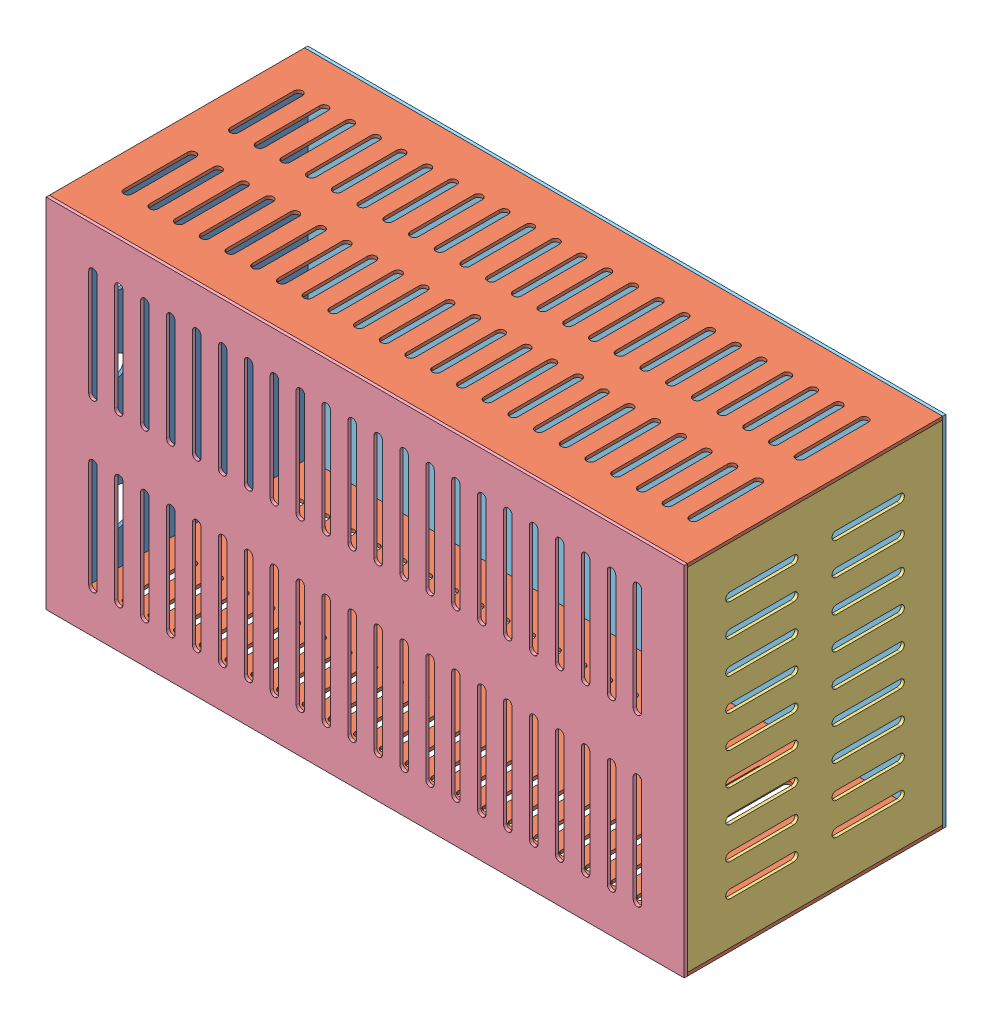
SolidWorks assembly battery, configuration Varsayılan. Lengths in mm.
Overall size (600 336 246).
6 component instances, 5 part files, 17 mates.
Components (placement in the parent):
- 330x240on kapak-2: 330x240on kapak [Varsayılan] at (-381.6411 -16.9017 813.542) x (0 -1 0) z (0 0 -1) size (330 3 240)
- 600x240-1: 600x240 [Varsayılan] at (-384.6411 -16.9017 573.542) size (600 3 240)
- 600x240-2: 600x240 [Varsayılan] at (-384.6411 -349.9017 573.542) size (600 3 240)
- 330x240-1: 330x240 [Varsayılan] at (212.3589 -346.9017 813.542) x (1 0 0) z (0 -1 0) size (3 240 330)
- 600x336-2: 600x336 [Varsayılan] at (-384.6411 -13.9017 813.542) size (600 336 3)
- 600x336ust-1: 600x336ust [Varsayılan] at (-384.6411 -13.9017 570.542) size (600 336 3)
Mates (geometry in assembly coordinates):
- Çakışık22: coincident aligned: plane of 600x240-2 through (215.3589 -346.9017 573.542) normal (1 0 0); plane of 330x240-1 through (215.3589 -346.9017 813.542) normal (1 0 0)
- Çakışık23: coincident anti-aligned: plane of 600x240-2 through (-384.6411 -346.9017 573.542) normal (0 1 0); plane of 330x240-1 through (215.3589 -346.9017 813.542) normal (0 -1 0)
- Çakışık24: coincident aligned: plane of 600x240-2 through (-384.6411 -346.9017 813.542) normal (0 0 1); plane of 330x240-1 through (215.3589 -346.9017 813.542) normal (0 0 1)
- Çakışık25: coincident aligned: plane of 600x240-1 through (215.3589 -13.9017 573.542) normal (1 0 0); plane of 330x240-1 through (215.3589 -346.9017 813.542) normal (1 0 0)
- Çakışık26: coincident aligned: plane of 600x240-1 through (-384.6411 -13.9017 813.542) normal (0 0 1); plane of 330x240-1 through (215.3589 -346.9017 813.542) normal (0 0 1)
- Çakışık27: coincident anti-aligned: plane of 600x240-1 through (-384.6411 -16.9017 573.542) normal (0 -1 0); plane of 330x240-1 through (215.3589 -16.9017 813.542) normal (0 1 0)
- Çakışık28: coincident aligned: plane of 330x240on kapak-2 through (-384.6411 -16.9017 813.542) normal (0 0 1); plane of 600x240-1 through (-384.6411 -13.9017 813.542) normal (0 0 1)
- Çakışık29: coincident anti-aligned: plane of 330x240on kapak-2 through (-384.6411 -16.9017 813.542) normal (0 1 0); plane of 600x240-1 through (-384.6411 -16.9017 573.542) normal (0 -1 0)
- Çakışık30: coincident anti-aligned: plane of 330x240on kapak-2 through (-384.6411 -346.9017 813.542) normal (0 -1 0); plane of 600x240-2 through (-384.6411 -346.9017 573.542) normal (0 1 0)
- Çakışık31: coincident aligned: plane of 330x240on kapak-2 through (-384.6411 -16.9017 813.542) normal (0 0 1); plane of 600x240-2 through (-384.6411 -346.9017 813.542) normal (0 0 1)
- Çakışık32: coincident aligned: plane of 330x240on kapak-2 through (-384.6411 -16.9017 813.542) normal (-1 0 0); plane of 600x240-1 through (-384.6411 -13.9017 573.542) normal (-1 0 0)
- Çakışık33: coincident aligned: plane of 600x240-1 through (-384.6411 -13.9017 573.542) normal (0 1 0); plane of 600x336-2 through (-384.6411 -13.9017 816.542) normal (0 1 0)
- Çakışık34: coincident aligned: plane of 330x240-1 through (215.3589 -346.9017 813.542) normal (1 0 0); plane of 600x336-2 through (215.3589 -13.9017 816.542) normal (1 0 0)
- Çakışık35: coincident anti-aligned: plane of 330x240-1 through (215.3589 -346.9017 813.542) normal (0 0 1); plane of 600x336-2 through (-384.6411 -13.9017 813.542) normal (0 0 -1)
- Çakışık36: coincident anti-aligned: plane of 600x240-2 through (-384.6411 -346.9017 573.542) normal (0 0 -1); plane of 600x336ust-1 through (-384.6411 -13.9017 573.542) normal (0 0 1)
- Çakışık37: coincident aligned: plane of 600x240-2 through (-384.6411 -349.9017 573.542) normal (0 -1 0); plane of 600x336ust-1 through (-384.6411 -349.9017 573.542) normal (0 -1 0)
- Çakışık38: coincident aligned: plane of 330x240-1 through (215.3589 -346.9017 813.542) normal (1 0 0); plane of 600x336ust-1 through (215.3589 -13.9017 573.542) normal (1 0 0)
